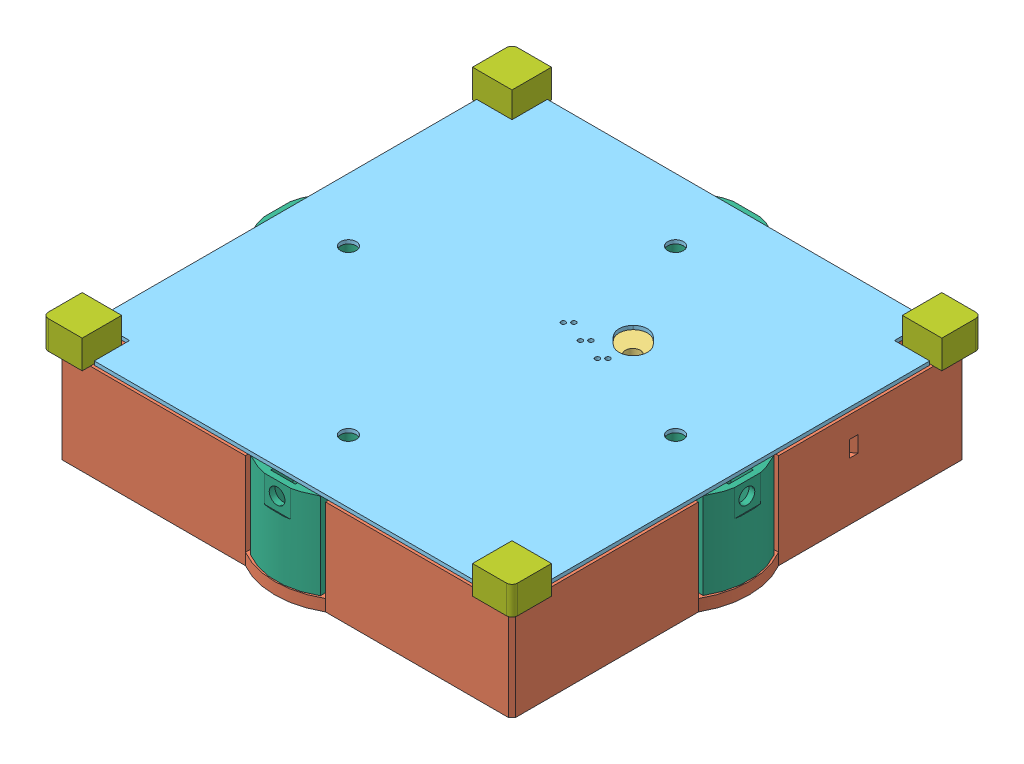
SolidWorks assembly UpdatedDeployerAssemblyV2, configuration Default. Lengths in mm.
Overall size (102.1 36.2 102.1).
16 component instances, 11 part files, 41 mates.
Components (placement in the parent):
- Bolt,8mm_x_24.6mm-1: Bolt,8mm_x_24.6mm [Default] at (87.4327 48.1765 67.9049) x (-0.932008 0 0.362436) z (0.362436 0 0.932008) size (13.7 30.1 13.7)
- DeployerBase-1: DeployerBase [Default] at (87.4327 27.6765 34.1549) size (102.1 20.5 102.1)
- CapNut,8mm-1: CapNut,8mm [Default] at (83.2758 27.6765 68.7713) x (-0.832874 0 -0.553463) z (-0.553463 0 0.832874) (suppressed, hidden)
- TopClasp-1: TopClasp [Default] at (81.3802 43.5765 59.4298) x (-0.707107 0 0.707107) z (-0.707107 0 -0.707107) size (40.5 5.1 18.35)
- BottomClasp-1: BottomClasp [Default] at (259.1309 43.5765 163.4899) x (-0.709165 0 0.705042) z (-0.705042 0 -0.709165) size (40.5 5.1 18.15)
- Nut,8mm-1: Nut,8mm [Default] at (90.5973 30.4801 70.736) x (0.998068 0 -0.062128) z (0.062128 0 0.998068) (suppressed, hidden)
- CoverPlate-1: CoverPlate [Default] at (87.4327 49.5765 67.9049) x (0 0 -1) z (0 -1 0) size (97.5 97.5 0.8)
- Washer,8mm-1: Washer,8mm [Default] at (87.4327 37.6801 67.9049) x (0.873012 0 0.487699) z (0.487699 0 -0.873012) (suppressed, hidden)
- RetentionPlate-1: RetentionPlate [Default] at (87.4327 43.5765 67.9049) x (0 0 -1) z (-1 0 0) size (101.64 18.6 101.64)
- Body1-2: Body1 [Default] at (87.6135 74.7765 102.1049) x (1 0 0) z (0 0 -1) size (8.5 6.1 8.5)
- Body1-3: Body1 [Default] at (87.2518 74.7765 33.7049) x (-1 0 0) z (0 0 1) size (8.5 6.1 8.5)
- Body1-4: Body1 [Default] at (121.6327 74.7765 67.7241) x (0 0 -1) z (-1 0 0) size (8.5 6.1 8.5)
- Body1-5: Body1 [Default] at (53.2327 74.7765 68.0858) x (0 0 1) z (1 0 0) size (8.5 6.1 8.5)
- Nut,3mm-1: Nut,3mm [Default] at (97.8786 29.4765 91.046) x (0.983955 0 -0.178418) z (0.178418 0 0.983955) size (6.06 2.2 7) (hidden)
- Nut,3mm-2: Nut,3mm [Default] at (75.099 29.4765 54.6665) x (-0.632747 0 -0.774359) z (0.774359 0 -0.632747) size (6.06 2.2 7) (hidden)
- Nut,3mm-3: Nut,3mm [Default] at (108.1355 27.2765 71.2567) x (0.926684 0 0.375842) z (-0.375842 0 0.926684) size (6.06 2.2 7) (hidden)
Mates (geometry in assembly coordinates):
- Parallel2: parallel anti-aligned: plane of DeployerBase-1 through (87.4327 27.6765 34.1549) normal (0 -1 0); plane of assembly through (0 0 0) normal (0 1 0)
- Concentric11: concentric aligned: cylinder of Bolt,8mm_x_24.6mm-1 through (87.4327 18.0765 67.9049) axis (0 1 0) radius 3.9; cylinder of Washer,8mm-1 through (87.4327 28.8801 67.9049) axis (0 1 0) radius 4.15
- Concentric12: concentric anti-aligned: cylinder of Bolt,8mm_x_24.6mm-1 through (87.4327 18.0765 67.9049) axis (0 1 0) radius 3.9; cylinder of Nut,8mm-1 through (87.4327 37.1801 67.9049) axis (0 -1 0) radius 4.05
- Concentric13: concentric aligned: cylinder of Bolt,8mm_x_24.6mm-1 through (87.4327 18.0765 67.9049) axis (0 1 0) radius 3.9; cylinder of CapNut,8mm-1 through (87.4327 20.9765 67.9049) axis (0 1 0) radius 4.05
- Coincident14: coincident anti-aligned: plane of Nut,8mm-1 through (90.5973 30.4801 70.736) normal (0 -1 0); plane of Washer,8mm-1 through (87.4327 30.4801 67.9049) normal (0 1 0)
- Coincident16: coincident anti-aligned: plane of DeployerBase-1 through (87.4327 27.6765 34.1549) normal (0 -1 0); plane of CapNut,8mm-1 through (83.2758 27.6765 68.7713) normal (0 1 0)
- Parallel4: parallel aligned: plane of DeployerBase-1 through (136.1827 48.1765 34.1549) normal (1 0 0); plane of assembly through (0 0 0) normal (1 0 0)
- Coincident22: coincident anti-aligned: plane of DeployerBase-1 through (87.4327 30.1765 34.1549) normal (0 1 0); plane of RetentionPlate-1 through (51.413 30.1765 67.9928) normal (0 -1 0)
- Concentric16: concentric anti-aligned: circle of DeployerBase-1; circle of RetentionPlate-1
- Coincident27: coincident anti-aligned: plane of DeployerBase-1 through (38.6827 48.1765 19.8549) normal (0 1 0); plane of Body1-5 through (38.1327 48.1765 117.2049) normal (0 -1 0)
- Coincident28: coincident anti-aligned: plane of DeployerBase-1 through (38.6827 48.1765 19.8549) normal (0 1 0); plane of Body1-3 through (38.1327 48.1765 18.6049) normal (0 -1 0)
- Coincident29: coincident anti-aligned: plane of DeployerBase-1 through (38.6827 48.1765 19.8549) normal (0 1 0); plane of Body1-2 through (136.7327 48.1765 117.2049) normal (0 -1 0)
- Coincident30: coincident anti-aligned: plane of DeployerBase-1 through (38.6827 48.1765 19.8549) normal (0 1 0); plane of Body1-4 through (136.7327 48.1765 18.6049) normal (0 -1 0)
- Distance1: distance = 1.75 mm aligned: plane of Body1-2 through (129.4327 48.1765 118.4049) normal (0 0 1); plane of DeployerBase-1 through (87.4327 48.1765 116.6549) normal (0 0 1)
- Distance2: distance = 1.75 mm aligned: plane of Body1-2 through (137.9327 48.1765 117.2049) normal (1 0 0); plane of DeployerBase-1 through (136.1827 48.1765 34.1549) normal (1 0 0)
- Distance3: distance = 1.75 mm aligned: plane of Body1-5 through (38.1327 48.1765 118.4049) normal (0 0 1); plane of DeployerBase-1 through (87.4327 48.1765 116.6549) normal (0 0 1)
- Distance5: distance = 1.75 mm aligned: plane of Body1-5 through (36.9327 48.1765 109.9049) normal (-1 0 0); plane of DeployerBase-1 through (38.6827 48.1765 34.1549) normal (-1 0 0)
- Distance6: distance = 1.75 mm aligned: plane of Body1-3 through (45.4327 48.1765 17.4049) normal (0 0 -1); plane of DeployerBase-1 through (87.4327 48.1765 19.1549) normal (0 0 -1)
- Distance7: distance = 1.75 mm aligned: plane of Body1-3 through (36.9327 48.1765 18.6049) normal (-1 0 0); plane of DeployerBase-1 through (38.6827 48.1765 34.1549) normal (-1 0 0)
- Distance9: distance = 1.75 mm aligned: plane of Body1-4 through (137.9327 48.1765 25.9049) normal (1 0 0); plane of DeployerBase-1 through (136.1827 48.1765 34.1549) normal (1 0 0)
- Distance10: distance = 1.75 mm aligned: plane of Body1-4 through (136.7327 48.1765 17.4049) normal (0 0 -1); plane of DeployerBase-1 through (87.4327 48.1765 19.1549) normal (0 0 -1)
- Coincident46: coincident aligned: cylinder of Bolt,8mm_x_24.6mm-1 through (87.4327 18.0765 67.9049) axis (0 1 0) radius 3.9; circle of DeployerBase-1
- Parallel8: parallel anti-aligned: plane of DeployerBase-1 through (96.0518 -119.2147 34.1549) normal (-1 0 0); plane of RetentionPlate-1 through (94.9825 48.7765 19.2083) normal (1 0 0)
- Parallel9: parallel anti-aligned: plane of DeployerBase-1 through (96.0518 -119.2147 34.1549) normal (-1 0 0); plane of RetentionPlate-1 through (94.9825 48.7765 19.2083) normal (1 0 0)
- Coincident56: coincident anti-aligned: plane of TopClasp-1 through (81.3802 43.5765 59.4298) normal (0 -1 0); plane of RetentionPlate-1 through (87.4327 43.5765 67.9049) normal (0 1 0)
- Concentric24: concentric aligned: cylinder of RetentionPlate-1 through (100.4434 30.1755 54.8942) axis (0 1 0) radius 1.6; circle of Nut,3mm-3
- Parallel13: parallel anti-aligned: plane of RetentionPlate-1 through (104.3891 50.1833 54.345) normal (-0.926684 0 -0.375842); plane of Nut,3mm-3 through (102.5946 39.3765 57.6551) normal (0.926684 0 0.375842)
- Coincident68: coincident anti-aligned: plane of RetentionPlate-1 through (87.4327 39.3765 67.9049) normal (0 -1 0); plane of Nut,3mm-3 through (101.2126 39.3765 56.5304) normal (0 1 0)
- Concentric25: concentric aligned: circle of RetentionPlate-1; circle of Nut,3mm-2
- Concentric26: concentric aligned: circle of RetentionPlate-1; circle of Nut,3mm-1
- Parallel14: parallel anti-aligned: plane of RetentionPlate-1 through (86.3744 25.5271 82.6843) normal (-0.646492 0 -0.762921); plane of Nut,3mm-1 through (83.2488 41.5765 84.7838) normal (0.646492 0 0.762921)
- Coincident70: coincident anti-aligned: plane of RetentionPlate-1 through (87.4327 41.5765 67.9049) normal (0 -1 0); plane of Nut,3mm-1 through (84.1498 41.5765 82.3106) normal (0 1 0)
- Parallel16: parallel anti-aligned: plane of RetentionPlate-1 through (70.2723 25.5271 71.3021) normal (0.632747 0 0.774359); plane of Nut,3mm-2 through (73.4349 41.5765 69.2588) normal (-0.632747 0 -0.774359)
- Coincident74: coincident anti-aligned: plane of RetentionPlate-1 through (87.4327 41.5765 67.9049) normal (0 -1 0); plane of Nut,3mm-2 through (74.1078 41.5765 70.9086) normal (0 1 0)
- Concentric27: concentric aligned: cylinder of BottomClasp-1 through (82.6243 43.5765 81.34) axis (0 1 0) radius 1.6; cylinder of RetentionPlate-1 through (82.6243 30.1755 81.34) axis (0 1 0) radius 1.6
- Concentric28: concentric aligned: cylinder of TopClasp-1 through (73.9976 43.5765 72.7133) axis (0 1 0) radius 1.6; cylinder of RetentionPlate-1 through (73.9976 30.1755 72.7133) axis (0 1 0) radius 1.6
- Coincident77: coincident anti-aligned: plane of BottomClasp-1 through (259.1309 43.5765 163.4899) normal (0 -1 0); plane of RetentionPlate-1 through (87.4327 43.5765 67.9049) normal (0 1 0)
- Lock2: lock: unknown of DeployerBase-1
- Coincident81: coincident aligned: plane of DeployerBase-1 through (136.1827 48.1765 34.1549) normal (1 0 0); plane of CoverPlate-1 through (136.1827 48.7765 19.1549) normal (1 0 0)
- Coincident82: coincident aligned: plane of DeployerBase-1 through (87.4327 48.1765 116.6549) normal (0 0 1); plane of CoverPlate-1 through (38.6827 48.7765 116.6549) normal (0 0 1)
- Coincident83: coincident anti-aligned: plane of CoverPlate-1 through (87.4327 48.7765 67.9049) normal (0 -1 0); plane of RetentionPlate-1 through (51.413 48.7765 67.9928) normal (0 1 0)
